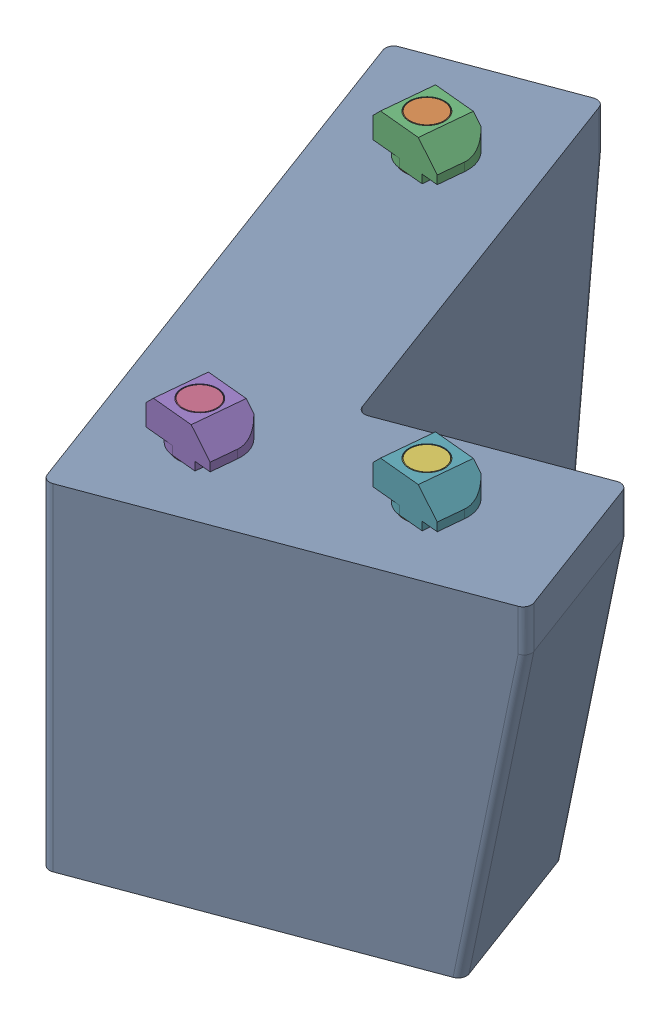
SolidWorks assembly back_left_foot, configuration Default. Lengths in mm.
Overall size (66.63 45 81.31).
7 component instances, 3 part files, 0 mates.
Components (placement in the parent):
- budget_foot_Back Left Foot-1: budget_foot_Back Left Foot [Default] at (48.5195 276.9149 220.3464) x (0.936903 0 -0.349591) z (0.349591 0 0.936903) size (45 40 70)
- m5_low_profile_screw_template_M5 x 10-1: m5_low_profile_screw_template_M5 x 10 [Default] at (38.3115 281.9149 164.384) x (0 1 0) z (-0.452256 0 0.891888) size (11.62 9 9)
- m5_locking_t_nut_20x20_generic-1: m5_locking_t_nut_20x20_generic [Default] at (38.0248 281.9149 167.3702) x (0.995423 0 0.095564) z (0.095564 0 -0.995423) size (10 4.5 6)
- m5_low_profile_screw_template_M5 x 10-2: m5_low_profile_screw_template_M5 x 10 [Default] at (54.3926 281.9149 207.4815) x (0 1 0) z (-0.452256 0 0.891888) size (11.62 9 9)
- m5_locking_t_nut_20x20_generic-2: m5_locking_t_nut_20x20_generic [Default] at (54.1059 281.9149 210.4678) x (0.995423 0 0.095564) z (0.095564 0 -0.995423) size (10 4.5 6)
- m5_low_profile_screw_template_M5 x 10-3: m5_low_profile_screw_template_M5 x 10 [Default] at (74.0676 281.9149 200.1401) x (0 1 0) z (-0.452256 0 0.891888) size (11.62 9 9)
- m5_locking_t_nut_20x20_generic-3: m5_locking_t_nut_20x20_generic [Default] at (73.7809 281.9149 203.1264) x (0.995423 0 0.095564) z (0.095564 0 -0.995423) size (10 4.5 6)
